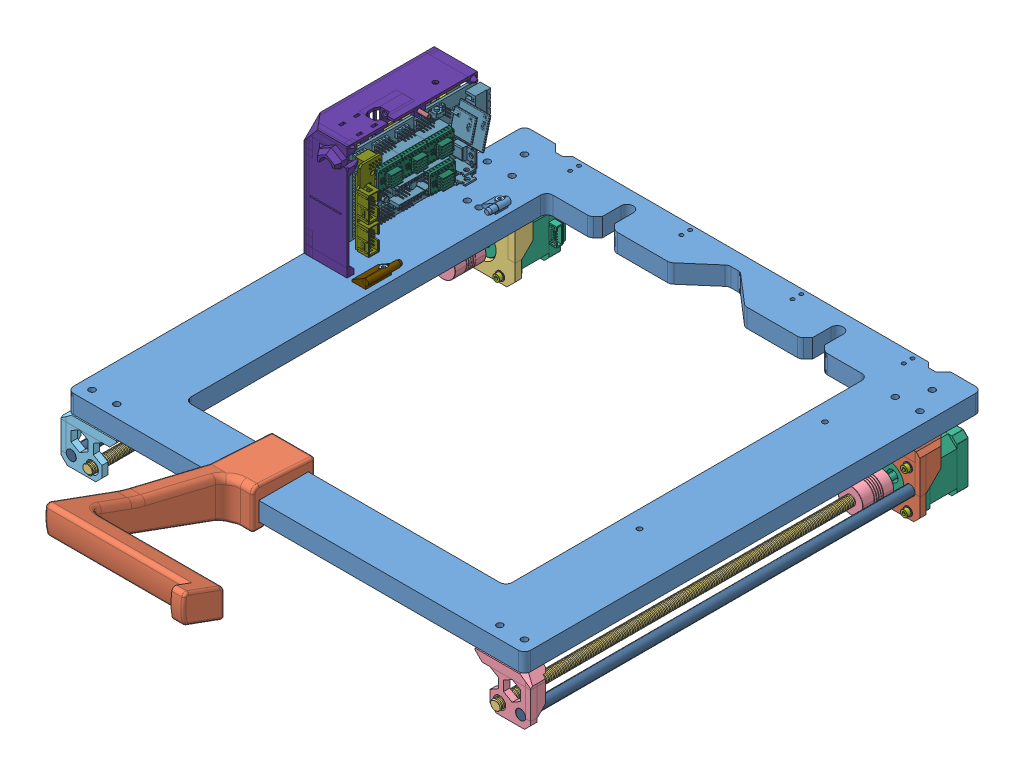
SolidWorks assembly Assembly z-axis, configuration Valor predeterminado. Lengths in mm.
Overall size (380.01 157.31 521.1).
83 component instances, 23 part files, 165 mates.
Components (placement in the parent):
- frame-2: frame [Valor predeterminado] at (-230.9594 15 -50.5362) x (1 0 0) z (0 -1 0) size (370 370 15)
- z-axis-bottom-A-1: z-axis-bottom-A [Valor predeterminado] at (185 0 55) x (0 -1 0) z (0 0 -1) size (50 52.51 38)
- z-axis-bottom-B-1: z-axis-bottom-B [Valor predeterminado] at (-198 0 55) x (0 -1 0) z (0 0 -1) size (50 52.51 38)
- z-axis-top-A-1: z-axis-top-A [Valor predeterminado] at (185 0 370) x (0 -1 0) z (0 0 -1) size (39.42 45.01 17.54)
- z-axis-top-B-1: z-axis-top-B [Valor predeterminado] at (-198 0 370) x (0 -1 0) z (0 0 -1) size (39.42 45.01 17.54)
- Stepper motor Nema 17-1: Stepper motor Nema 17 [Valor predeterminado] at (-169.2544 -5.1722 37.5) x (0 0 -1) z (1 0 0) size (62.01 42.01 48.01)
- Stepper motor Nema 17-2: Stepper motor Nema 17 [Valor predeterminado] at (169.2544 -53.4278 37.5) x (0 0 -1) z (-1 0 0) size (62.01 42.01 48.01)
- Screw DIN 912 - M3 x 10 --- 10N-1: Screw DIN 912 - M3 x 10 --- 10N [Valor predeterminado] at (-180.5 -13.8 58.5) x (0 0 1) z (-0.056546 -0.9984 0) size (13 5.5 5.5)
- Washer DIN 125A - M3-1: Washer DIN 125A - M3 [Valor predeterminado] at (-180.5 -13.8 55) x (0 0 1) z (-0.999462 0.03279 0) size (0.5 7 7)
- Screw DIN 912 - M3 x 10 --- 10N-2: Screw DIN 912 - M3 x 10 --- 10N [Valor predeterminado] at (-180.5 -44.8 58.5) x (0 0 1) z (-0.056546 -0.9984 0) size (13 5.5 5.5)
- Washer DIN 125A - M3-2: Washer DIN 125A - M3 [Valor predeterminado] at (-180.5 -44.8 55) x (0 0 1) z (-0.999462 0.03279 0) size (0.5 7 7)
- Screw DIN 912 - M3 x 10 --- 10N-3: Screw DIN 912 - M3 x 10 --- 10N [Valor predeterminado] at (-149.5 -13.8 58.5) x (0 0 1) z (-0.056546 -0.9984 0) size (13 5.5 5.5)
- Washer DIN 125A - M3-3: Washer DIN 125A - M3 [Valor predeterminado] at (-149.5 -13.8 55) x (0 0 1) z (-0.999462 0.03279 0) size (0.5 7 7)
- Screw DIN 912 - M3 x 10 --- 10N-4: Screw DIN 912 - M3 x 10 --- 10N [Valor predeterminado] at (-149.5 -44.8 58.5) x (0 0 1) z (-0.056546 -0.9984 0) size (13 5.5 5.5)
- Washer DIN 125A - M3-4: Washer DIN 125A - M3 [Valor predeterminado] at (-149.5 -44.8 55) x (0 0 1) z (-0.999462 0.03279 0) size (0.5 7 7)
- Screw DIN 912 - M3 x 10 --- 10N-5: Screw DIN 912 - M3 x 10 --- 10N [Valor predeterminado] at (149.5 -13.8 58.5) x (0 0 1) z (-0.056546 -0.9984 0) size (13 5.5 5.5)
- Washer DIN 125A - M3-5: Washer DIN 125A - M3 [Valor predeterminado] at (149.5 -13.8 55) x (0 0 1) z (-0.999462 0.03279 0) size (0.5 7 7)
- Screw DIN 912 - M3 x 10 --- 10N-6: Screw DIN 912 - M3 x 10 --- 10N [Valor predeterminado] at (180.5 -44.8 58.5) x (0 0 1) z (-0.056546 -0.9984 0) size (13 5.5 5.5)
- Washer DIN 125A - M3-6: Washer DIN 125A - M3 [Valor predeterminado] at (180.5 -44.8 55) x (0 0 1) z (-0.999462 0.03279 0) size (0.5 7 7)
- Screw DIN 912 - M3 x 10 --- 10N-7: Screw DIN 912 - M3 x 10 --- 10N [Valor predeterminado] at (149.5 -44.8 58.5) x (0 0 1) z (-0.056546 -0.9984 0) size (13 5.5 5.5)
- Washer DIN 125A - M3-7: Washer DIN 125A - M3 [Valor predeterminado] at (149.5 -44.8 55) x (0 0 1) z (-0.999462 0.03279 0) size (0.5 7 7)
- Screw DIN 912 - M3 x 10 --- 10N-8: Screw DIN 912 - M3 x 10 --- 10N [Valor predeterminado] at (180.5 -13.8 58.5) x (0 0 1) z (-0.056546 -0.9984 0) size (13 5.5 5.5)
- Washer DIN 125A - M3-8: Washer DIN 125A - M3 [Valor predeterminado] at (180.5 -13.8 55) x (0 0 1) z (-0.999462 0.03279 0) size (0.5 7 7)
- Nut DIN 934 - M3-1: Nut DIN 934 - M3 [Valor predeterminado] at (165 6.2 20) x (0 1 0) z (0.5 0 0.866025) size (2.4 5.5 6.35)
- Nut DIN 934 - M3-2: Nut DIN 934 - M3 [Valor predeterminado] at (155 6.2 40) x (0 1 0) z (0.5 0 0.866025) size (2.4 5.5 6.35)
- Nut DIN 934 - M3-3: Nut DIN 934 - M3 [Valor predeterminado] at (175 6.2 40) x (0 1 0) z (1 0 0) size (2.4 5.5 6.35)
- Nut DIN 934 - M3-4: Nut DIN 934 - M3 [Valor predeterminado] at (-165 6.2 20) x (0 1 0) z (0.5 0 -0.866025) size (2.4 5.5 6.35)
- Nut DIN 934 - M3-5: Nut DIN 934 - M3 [Valor predeterminado] at (-175 6.2 40) x (0 1 0) z (0.5 0 0.866025) size (2.4 5.5 6.35)
- Nut DIN 934 - M3-6: Nut DIN 934 - M3 [Valor predeterminado] at (-155 6.2 40) x (0 1 0) z (1 0 0) size (2.4 5.5 6.35)
- Nut DIN 934 - M3-7: Nut DIN 934 - M3 [Valor predeterminado] at (175 6.2 360) x (0 1 0) z (1 0 0) size (2.4 5.5 6.35)
- Nut DIN 934 - M3-11: Nut DIN 934 - M3 [Valor predeterminado] at (155 6.2 360) x (0 1 0) z (1 0 0) size (2.4 5.5 6.35)
- Nut DIN 934 - M3-12: Nut DIN 934 - M3 [Valor predeterminado] at (-155 6.2 360) x (0 1 0) z (0.5 0 -0.866025) size (2.4 5.5 6.35)
- Nut DIN 934 - M3-13: Nut DIN 934 - M3 [Valor predeterminado] at (-175 6.2 360) x (0 1 0) z (-0.5 0 -0.866025) size (2.4 5.5 6.35)
- Smooth Rod - 8 x 320-1: Smooth Rod - 8 x 320 [Valor predeterminado] at (-182 -29.3 210) x (0.837139 0.54699 0) z (0 0 1) size (8 8 320)
- Smooth Rod - 8 x 320-2: Smooth Rod - 8 x 320 [Valor predeterminado] at (182 -29.3 210) x (-0.0626 0.998039 0) z (0 0 1) size (8 8 320)
- Microswitch with leaver - KW11-3Z 5A 250VAC-1: Microswitch with leaver - KW11-3Z 5A 250VAC [Valor predeterminado] at (-150.8125 -3.2 77.7125) x (-1 0 0) z (0 1 0) size (21.17 22.83 6.4)
- Nut DIN 934 - M3-15: Nut DIN 934 - M3 [Valor predeterminado] at (-146.25 6.2 75.5) x (0 1 0) z (-0.866025 0 -0.5) size (2.4 5.5 6.35)
- Nut DIN 934 - M3-16: Nut DIN 934 - M3 [Valor predeterminado] at (-155.75 6.2 75.5) x (0 1 0) z (-0.866025 0 -0.5) size (2.4 5.5 6.35)
- Assembly ramps-base-1: Assembly ramps-base [Valor predeterminado] at (-197.9193 45.3991 169.7915) x (0 0 -1) z (1 0 0) size (130.96 92 50.19)
  - Arduino Mega 2560-1: Arduino Mega 2560 [Valor predeterminado] at (57.1056 8.769 22.4871) x (1 0 0) z (0 0 -1) size (107.95 53.42 12.95)
  - Screw DIN 912 - M3 x 10 --- 10N-1: Screw DIN 912 - M3 x 10 --- 10N [Valor predeterminado] at (18.65 -15.3991 25.4871) x (0 0 1) z (-0.998601 -0.052872 0) size (13 5.5 5.5)
  - Nut DIN 934 - M3-1: Nut DIN 934 - M3 [Valor predeterminado] at (18.65 -15.3991 14.6361) x (0 0 1) z (-0.5 0.866025 0) size (2.4 5.5 6.35)
  - Nut DIN 934 - M3-2: Nut DIN 934 - M3 [Valor predeterminado] at (93.7832 -15.3991 14.6361) x (0 0 1) z (0.5 0.866025 0) size (2.4 5.5 6.35)
  - Nut DIN 934 - M3-3: Nut DIN 934 - M3 [Valor predeterminado] at (93.7832 32.9371 14.6361) x (0 0 1) z (0.5 0.866025 0) size (2.4 5.5 6.35)
  - Nut DIN 934 - M3-4: Nut DIN 934 - M3 [Valor predeterminado] at (11.157 32.9371 14.6361) x (0 0 1) z (1 0 0) size (2.4 5.5 6.35)
  - Screw DIN 912 - M3 x 10 --- 10N-2: Screw DIN 912 - M3 x 10 --- 10N [Valor predeterminado] at (93.7832 -15.3991 25.4871) x (0 0 1) z (-0.973921 -0.226886 0) size (13 5.5 5.5)
  - Screw DIN 912 - M3 x 10 --- 10N-3: Screw DIN 912 - M3 x 10 --- 10N [Valor predeterminado] at (11.157 32.9371 25.4871) x (0 0 1) z (0.550712 0.834695 0) size (13 5.5 5.5)
  - Screw DIN 912 - M3 x 10 --- 10N-4: Screw DIN 912 - M3 x 10 --- 10N [Valor predeterminado] at (93.7832 32.9371 25.4871) x (0 0 1) z (0.550712 0.834695 0) size (13 5.5 5.5)
  - Screw DIN 912 - M3 x 40 --- 18N-1: Screw DIN 912 - M3 x 40 --- 18N [Valor predeterminado] at (49.8 57.6009 12.8361) x (0 0 -1) z (0.83561 0.549324 0) size (43 5.5 5.5)
  - Shield Ramps 1.4-2: Shield Ramps 1.4 [Valor predeterminado] at (108.7635 12.736 33.6033) x (0 1 0) z (1 0 0) size (61.76 37.63 106.38)
  - Driver A4988-1: Driver A4988 [Valor predeterminado] at (87.8289 82.4643 46.4093) x (-1 0 0) z (0 0 1) size (20.32 15.24 16.04)
  - Driver A4988-2: Driver A4988 [Valor predeterminado] at (108.1489 82.4643 46.4093) x (-1 0 0) z (0 0 1) size (20.32 15.24 16.04)
  - Driver A4988-3: Driver A4988 [Valor predeterminado] at (128.4689 82.4643 46.4093) x (-1 0 0) z (0 0 1) size (20.32 15.24 16.04)
  - Driver A4988-4: Driver A4988 [Valor predeterminado] at (129.5994 59.472 46.4093) x (-1 0 0) z (0 0 1) size (20.32 15.24 16.04)
  - Smart adapter conector LCD Ramps 1.4-1: Smart adapter conector LCD Ramps 1.4 [Valor predeterminado] at (11.3811 33.5685 46.6805) x (-1 0 0) z (0 1 0) size (20.12 19 60.45)
  - RAMPS-cover-base-3: RAMPS-cover-base [Valor predeterminado] at (-8.7 -30.3991 12.8361) size (126.5 92 38)
- Nut DIN 934 - M3-17: Nut DIN 934 - M3 [Valor predeterminado] at (-180.0832 20.2 161.9916) x (0 -1 0) z (0.866025 0 -0.5) size (2.4 5.5 6.35)
- Nut DIN 934 - M3-18: Nut DIN 934 - M3 [Valor predeterminado] at (-180.0832 20.2 67.9916) x (0 1 0) z (0 0 1) size (2.4 5.5 6.35)
- RAMPS-cover-hinges-A-1: RAMPS-cover-hinges-A [Valor predeterminado] at (-134.5485 20 178.9653) x (0 1 0) z (0 0 -1) size (7.4 13.4 28)
- RAMPS-cover-hinges-B-1: RAMPS-cover-hinges-B [Valor predeterminado] at (-128.5485 20 63.9653) x (0 1 0) z (0 0 1) size (7.8 13.8 17)
- Nut DIN 934 - M3-19: Nut DIN 934 - M3 [Valor predeterminado] at (-137.0485 8.8 67.9653) x (0 -1 0) z (0 0 1) size (2.4 5.5 6.35)
- Nut DIN 934 - M3-20: Nut DIN 934 - M3 [Valor predeterminado] at (-137.0485 8.8 161.9653) x (0 -1 0) z (0.866025 0 0.5) size (2.4 5.5 6.35)
- spool-holder-1: spool-holder [Valor predeterminado] at (-50 2.325 349.9) x (0 -1 0) z (-1 0 0) size (75.07 196.6 125)
- LeadScrew - 8 x 300-1: LeadScrew - 8 x 300 [Valor predeterminado] at (165 -29.3 373.6) x (0.509229 0.860631 0) z (0 0 1) size (9.24 8.22 301.1)
- LeadScrew - 8 x 300-2: LeadScrew - 8 x 300 [Valor predeterminado] at (-165 -29.3 373.6) x (-0.382268 -0.924051 0) z (0 0 1) size (9.24 8.22 301.1)
- Flexible coupler - 5 x 8-1: Flexible coupler - 5 x 8 [Valor predeterminado] at (-163.6049 -28.4539 61.1) x (0.99991 -0.013416 0) z (0 0 1) size (20 20.77 25)
- Flexible coupler - 5 x 8-2: Flexible coupler - 5 x 8 [Valor predeterminado] at (166.3519 -28.3864 61.1) x (0.999363 0.035693 0) z (0 0 1) size (20 20.77 25)
- Screw DIN 912 - M3 x 16 --- 16N-1: Screw DIN 912 - M3 x 16 --- 16N [Valor predeterminado] at (-155 -7 360) x (0 -1 0) z (-0.591205 0 0.806522) size (19 5.5 5.5)
- Screw DIN 912 - M3 x 16 --- 16N-2: Screw DIN 912 - M3 x 16 --- 16N [Valor predeterminado] at (-175 -7 360) x (0 -1 0) z (-0.591205 0 0.806522) size (19 5.5 5.5)
- Screw DIN 912 - M3 x 16 --- 16N-3: Screw DIN 912 - M3 x 16 --- 16N [Valor predeterminado] at (155 -7 360) x (0 -1 0) z (-0.591205 0 0.806522) size (19 5.5 5.5)
- Screw DIN 912 - M3 x 16 --- 16N-4: Screw DIN 912 - M3 x 16 --- 16N [Valor predeterminado] at (175 -7 360) x (0 -1 0) z (-0.591205 0 0.806522) size (19 5.5 5.5)
- Screw DIN 912 - M3 x 16 --- 16N-5: Screw DIN 912 - M3 x 16 --- 16N [Valor predeterminado] at (175 -7 40) x (0 -1 0) z (-0.591205 0 0.806522) size (19 5.5 5.5)
- Screw DIN 912 - M3 x 16 --- 16N-6: Screw DIN 912 - M3 x 16 --- 16N [Valor predeterminado] at (165 -7 20) x (0 -1 0) z (-0.591205 0 0.806522) size (19 5.5 5.5)
- Screw DIN 912 - M3 x 16 --- 16N-7: Screw DIN 912 - M3 x 16 --- 16N [Valor predeterminado] at (155 -7 40) x (0 -1 0) z (-0.591205 0 0.806522) size (19 5.5 5.5)
- Screw DIN 912 - M3 x 16 --- 16N-8: Screw DIN 912 - M3 x 16 --- 16N [Valor predeterminado] at (-155 -7 40) x (0 -1 0) z (-0.591205 0 0.806522) size (19 5.5 5.5)
- Screw DIN 912 - M3 x 16 --- 16N-9: Screw DIN 912 - M3 x 16 --- 16N [Valor predeterminado] at (-165 -7 20) x (0 -1 0) z (0.85743 0 -0.5146) size (19 5.5 5.5)
- Screw DIN 912 - M3 x 16 --- 16N-10: Screw DIN 912 - M3 x 16 --- 16N [Valor predeterminado] at (-175 -7 40) x (0 -1 0) z (-0.591205 0 0.806522) size (19 5.5 5.5)
- Screw DIN 912 - M3 x 16 --- 16N-11: Screw DIN 912 - M3 x 16 --- 16N [Valor predeterminado] at (-137.0485 22 67.9653) x (0 1 0) z (-0.552016 0 0.833834) size (19 5.5 5.5)
- Screw DIN 912 - M3 x 16 --- 16N-12: Screw DIN 912 - M3 x 16 --- 16N [Valor predeterminado] at (-137.0485 21 161.9653) x (0 1 0) z (0.888501 0 0.458875) size (19 5.5 5.5)
- Screw DIN 912 - M3 x 16 --- 16N-13: Screw DIN 912 - M3 x 16 --- 16N [Valor predeterminado] at (-146.225 -9.4 75.5) x (0 -1 0) z (0.477506 0 0.878629) size (19 5.5 5.5)
- Screw DIN 912 - M3 x 16 --- 16N-14: Screw DIN 912 - M3 x 16 --- 16N [Valor predeterminado] at (-155.75 -9.4 75.5) x (0 -1 0) z (-0.13071 0 0.991421) size (19 5.5 5.5)
- Screw DIN 912 - M3 x 16 --- 16N-15: Screw DIN 912 - M3 x 16 --- 16N [Valor predeterminado] at (-180.0832 7 67.9916) x (0 -1 0) z (-0.148109 0 0.988971) size (19 5.5 5.5)
- Screw DIN 912 - M3 x 16 --- 16N-16: Screw DIN 912 - M3 x 16 --- 16N [Valor predeterminado] at (-180.0485 7 161.9653) x (0 -1 0) z (0.028079 0 0.999606) size (19 5.5 5.5)
Mates (geometry in assembly coordinates):
- Coincidente1: coincident: plane of assembly through (0 0 0) normal (0 0 1); plane of frame-2 through (-160 0 0) normal (0 0 -1); plane of assembly
- Simétrico1: symmetric: plane of assembly; plane of assembly; plane of frame-2 through (185 0 365) normal (1 0 0); plane of frame-2 through (-185 0 5) normal (-1 0 0); plane of assembly
- Coincidente2: coincident: plane of assembly through (0 0 0) normal (0 1 0); plane of frame-2 through (180 0 365) normal (0 -1 0); plane of assembly
- Coincidente3: coincident: plane of assembly; plane of assembly; plane of frame-2 through (180 0 365) normal (0 -1 0); plane of z-axis-bottom-B-1 through (-186.5 0 55) normal (0 1 0)
- Coincidente4: coincident: plane of assembly; plane of assembly; plane of frame-2 through (180 0 365) normal (0 -1 0); plane of z-axis-bottom-A-1 through (186.5 0 55) normal (0 1 0)
- Coincidente5: coincident: plane of assembly through (0 0 0) normal (0 1 0); plane of z-axis-top-A-1 through (190 0 370) normal (0 1 0); plane of assembly
- Coincidente6: coincident: plane of assembly through (0 0 0) normal (0 1 0); plane of z-axis-top-B-1 through (-190 0 370) normal (0 1 0); plane of assembly
- Paralelo1: parallel: plane of assembly through (0 0 0) normal (0 0 1); plane of z-axis-bottom-A-1 through (186.5 0 55) normal (0 0 1); plane of assembly
- Paralelo2: parallel: plane of assembly through (0 0 0) normal (0 0 1); plane of z-axis-bottom-B-1 through (-186.5 0 55) normal (0 0 1); plane of assembly
- Concêntrico1: concentric: cylinder of assembly; cylinder of assembly; cylinder of frame-2 through (-165 0 20) axis (0 1 0) radius 1.5; cylinder of z-axis-bottom-B-1 through (-165 1 20) axis (0 -1 0) radius 1.8
- Concêntrico2: concentric: cylinder of assembly; cylinder of assembly; cylinder of frame-2 through (165 0 20) axis (0 1 0) radius 1.5; cylinder of z-axis-bottom-A-1 through (165 1 20) axis (0 -1 0) radius 1.8
- Paralelo3: parallel: plane of assembly through (0 0 0) normal (0 0 1); plane of z-axis-top-B-1 through (-190 0 370) normal (0 0 1); plane of assembly
- Paralelo4: parallel: plane of assembly through (0 0 0) normal (0 0 1); plane of z-axis-top-A-1 through (190 0 370) normal (0 0 1); plane of assembly
- Concêntrico3: concentric: cylinder of assembly; cylinder of assembly; cylinder of frame-2 through (-155 0 360) axis (0 1 0) radius 1.5; cylinder of z-axis-top-B-1 through (-155 1 360) axis (0 -1 0) radius 1.8
- Concêntrico4: concentric: cylinder of assembly; cylinder of assembly; cylinder of frame-2 through (155 0 360) axis (0 1 0) radius 1.5; cylinder of z-axis-top-A-1 through (155 1 360) axis (0 -1 0) radius 1.8
- Coincidente11: coincident: plane of assembly; plane of assembly; plane of z-axis-bottom-B-1 through (-190 0 50) normal (0 0 -1); plane of Stepper motor Nema 17-1 through (-165 -29.3 50) normal (0 0 1)
- Concêntrico5: concentric: cylinder of assembly; cylinder of assembly; cylinder of z-axis-bottom-B-1 through (-165 -29.3 57) axis (0 0 -1) radius 12; cylinder of Stepper motor Nema 17-1 through (-165 -29.3 50.85) axis (0 0 1) radius 11
- Concêntrico6: concentric: cylinder of assembly; cylinder of assembly; cylinder of z-axis-bottom-A-1 through (165 -29.3 57) axis (0 0 -1) radius 12; cylinder of Stepper motor Nema 17-2 through (165 -29.3 50.85) axis (0 0 1) radius 11
- Coincidente13: coincident: plane of assembly; plane of assembly; plane of z-axis-bottom-A-1 through (190 0 50) normal (0 0 -1); plane of Stepper motor Nema 17-2 through (165 -29.3 50) normal (0 0 1)
- Concêntrico7: concentric: cylinder of assembly; cylinder of assembly; cylinder of Screw DIN 912 - M3 x 10 --- 10N-1 through (-180.5 -13.8 58.5) axis (0 0 1) radius 1.5; cylinder of Washer DIN 125A - M3-1 through (-180.5 -13.8 55.5) axis (0 0 -1) radius 1.6
- Coincidente14: coincident: plane of assembly; plane of assembly; plane of Screw DIN 912 - M3 x 10 --- 10N-1 through (-183.2456 -13.6445 55.5) normal (0 0 -1); plane of Washer DIN 125A - M3-1 through (-180.5 -13.8 55.5) normal (0 0 1)
- Concêntrico8: concentric: cylinder of assembly; cylinder of assembly; cylinder of z-axis-bottom-B-1 through (-180.5 -13.8 57) axis (0 0 -1) radius 1.8; cylinder of Screw DIN 912 - M3 x 10 --- 10N-1 through (-180.5 -13.8 58.5) axis (0 0 1) radius 1.5
- Coincidente15: coincident: plane of assembly; plane of assembly; plane of z-axis-bottom-B-1 through (-190 0 55) normal (0 0 1); plane of Washer DIN 125A - M3-1 through (-180.5 -13.8 55) normal (0 0 -1)
- Concêntrico9: concentric: cylinder of assembly; cylinder of assembly; cylinder of Screw DIN 912 - M3 x 10 --- 10N-2 through (-180.5 -44.8 58.5) axis (0 0 1) radius 1.5; cylinder of Washer DIN 125A - M3-2 through (-180.5 -44.8 55.5) axis (0 0 -1) radius 1.6
- Coincidente16: coincident: plane of assembly; plane of assembly; plane of Screw DIN 912 - M3 x 10 --- 10N-2 through (-183.2456 -44.6445 55.5) normal (0 0 -1); plane of Washer DIN 125A - M3-2 through (-180.5 -44.8 55.5) normal (0 0 1)
- Concêntrico10: concentric: cylinder of assembly; cylinder of assembly; cylinder of Screw DIN 912 - M3 x 10 --- 10N-3 through (-149.5 -13.8 58.5) axis (0 0 1) radius 1.5; cylinder of Washer DIN 125A - M3-3 through (-149.5 -13.8 55.5) axis (0 0 -1) radius 1.6
- Coincidente17: coincident: plane of assembly; plane of assembly; plane of Screw DIN 912 - M3 x 10 --- 10N-3 through (-152.2456 -13.6445 55.5) normal (0 0 -1); plane of Washer DIN 125A - M3-3 through (-149.5 -13.8 55.5) normal (0 0 1)
- Concêntrico11: concentric: cylinder of assembly; cylinder of assembly; cylinder of Screw DIN 912 - M3 x 10 --- 10N-4 through (-149.5 -44.8 58.5) axis (0 0 1) radius 1.5; cylinder of Washer DIN 125A - M3-4 through (-149.5 -44.8 55.5) axis (0 0 -1) radius 1.6
- Coincidente18: coincident: plane of assembly; plane of assembly; plane of Screw DIN 912 - M3 x 10 --- 10N-4 through (-152.2456 -44.6445 55.5) normal (0 0 -1); plane of Washer DIN 125A - M3-4 through (-149.5 -44.8 55.5) normal (0 0 1)
- Concêntrico12: concentric: cylinder of assembly; cylinder of assembly; cylinder of z-axis-bottom-B-1 through (-180.5 -44.8 57) axis (0 0 -1) radius 1.8; cylinder of Screw DIN 912 - M3 x 10 --- 10N-2 through (-180.5 -44.8 58.5) axis (0 0 1) radius 1.5
- Concêntrico13: concentric: cylinder of assembly; cylinder of assembly; cylinder of z-axis-bottom-B-1 through (-149.5 -44.8 57) axis (0 0 -1) radius 1.8; cylinder of Screw DIN 912 - M3 x 10 --- 10N-4 through (-149.5 -44.8 58.5) axis (0 0 1) radius 1.5
- Concêntrico14: concentric: cylinder of assembly; cylinder of assembly; cylinder of z-axis-bottom-B-1 through (-149.5 -13.8 57) axis (0 0 -1) radius 1.8; cylinder of Screw DIN 912 - M3 x 10 --- 10N-3 through (-149.5 -13.8 58.5) axis (0 0 1) radius 1.5
- Coincidente19: coincident: plane of assembly; plane of assembly; plane of z-axis-bottom-B-1 through (-190 0 55) normal (0 0 1); plane of Washer DIN 125A - M3-4 through (-149.5 -44.8 55) normal (0 0 -1)
- Coincidente20: coincident: plane of assembly; plane of assembly; plane of z-axis-bottom-B-1 through (-190 0 55) normal (0 0 1); plane of Washer DIN 125A - M3-2 through (-180.5 -44.8 55) normal (0 0 -1)
- Coincidente21: coincident: plane of assembly; plane of assembly; plane of z-axis-bottom-B-1 through (-190 0 55) normal (0 0 1); plane of Washer DIN 125A - M3-3 through (-149.5 -13.8 55) normal (0 0 -1)
- Concêntrico15: concentric: cylinder of assembly; cylinder of assembly; cylinder of Screw DIN 912 - M3 x 10 --- 10N-5 through (149.5 -13.8 58.5) axis (0 0 1) radius 1.5; cylinder of Washer DIN 125A - M3-5 through (149.5 -13.8 55.5) axis (0 0 -1) radius 1.6
- Coincidente22: coincident: plane of assembly; plane of assembly; plane of Screw DIN 912 - M3 x 10 --- 10N-5 through (146.7544 -13.6445 55.5) normal (0 0 -1); plane of Washer DIN 125A - M3-5 through (149.5 -13.8 55.5) normal (0 0 1)
- Concêntrico16: concentric: cylinder of assembly; cylinder of assembly; cylinder of Screw DIN 912 - M3 x 10 --- 10N-6 through (180.5 -44.8 58.5) axis (0 0 1) radius 1.5; cylinder of Washer DIN 125A - M3-6 through (180.5 -44.8 55.5) axis (0 0 -1) radius 1.6
- Coincidente23: coincident: plane of assembly; plane of assembly; plane of Screw DIN 912 - M3 x 10 --- 10N-6 through (177.7544 -44.6445 55.5) normal (0 0 -1); plane of Washer DIN 125A - M3-6 through (180.5 -44.8 55.5) normal (0 0 1)
- Concêntrico17: concentric: cylinder of assembly; cylinder of assembly; cylinder of Screw DIN 912 - M3 x 10 --- 10N-7 through (149.5 -44.8 58.5) axis (0 0 1) radius 1.5; cylinder of Washer DIN 125A - M3-7 through (149.5 -44.8 55.5) axis (0 0 -1) radius 1.6
- Coincidente24: coincident: plane of assembly; plane of assembly; plane of Screw DIN 912 - M3 x 10 --- 10N-7 through (146.7544 -44.6445 55.5) normal (0 0 -1); plane of Washer DIN 125A - M3-7 through (149.5 -44.8 55.5) normal (0 0 1)
- Concêntrico18: concentric: cylinder of assembly; cylinder of assembly; cylinder of Screw DIN 912 - M3 x 10 --- 10N-8 through (180.5 -13.8 58.5) axis (0 0 1) radius 1.5; cylinder of Washer DIN 125A - M3-8 through (180.5 -13.8 55.5) axis (0 0 -1) radius 1.6
- Coincidente25: coincident: plane of assembly; plane of assembly; plane of Screw DIN 912 - M3 x 10 --- 10N-8 through (177.7544 -13.6445 55.5) normal (0 0 -1); plane of Washer DIN 125A - M3-8 through (180.5 -13.8 55.5) normal (0 0 1)
- Concêntrico19: concentric: cylinder of assembly; cylinder of assembly; cylinder of z-axis-bottom-A-1 through (149.5 -13.8 57) axis (0 0 -1) radius 1.8; cylinder of Screw DIN 912 - M3 x 10 --- 10N-5 through (149.5 -13.8 58.5) axis (0 0 1) radius 1.5
- Concêntrico20: concentric: cylinder of assembly; cylinder of assembly; cylinder of z-axis-bottom-A-1 through (180.5 -13.8 57) axis (0 0 -1) radius 1.8; cylinder of Screw DIN 912 - M3 x 10 --- 10N-8 through (180.5 -13.8 58.5) axis (0 0 1) radius 1.5
- Concêntrico21: concentric: cylinder of assembly; cylinder of assembly; cylinder of z-axis-bottom-A-1 through (180.5 -44.8 57) axis (0 0 -1) radius 1.8; cylinder of Screw DIN 912 - M3 x 10 --- 10N-6 through (180.5 -44.8 58.5) axis (0 0 1) radius 1.5
- Concêntrico22: concentric: cylinder of assembly; cylinder of assembly; cylinder of z-axis-bottom-A-1 through (149.5 -44.8 57) axis (0 0 -1) radius 1.8; cylinder of Screw DIN 912 - M3 x 10 --- 10N-7 through (149.5 -44.8 58.5) axis (0 0 1) radius 1.5
- Coincidente26: coincident: plane of assembly; plane of assembly; plane of z-axis-bottom-A-1 through (190 0 55) normal (0 0 1); plane of Washer DIN 125A - M3-6 through (180.5 -44.8 55) normal (0 0 -1)
- Coincidente27: coincident: plane of assembly; plane of assembly; plane of z-axis-bottom-A-1 through (190 0 55) normal (0 0 1); plane of Washer DIN 125A - M3-7 through (149.5 -44.8 55) normal (0 0 -1)
- Coincidente28: coincident: plane of assembly; plane of assembly; plane of z-axis-bottom-A-1 through (190 0 55) normal (0 0 1); plane of Washer DIN 125A - M3-5 through (149.5 -13.8 55) normal (0 0 -1)
- Coincidente29: coincident: plane of assembly; plane of assembly; plane of z-axis-bottom-A-1 through (190 0 55) normal (0 0 1); plane of Washer DIN 125A - M3-8 through (180.5 -13.8 55) normal (0 0 -1)
- Concêntrico62: concentric: cylinder of assembly; cylinder of assembly; cylinder of z-axis-bottom-B-1 through (-182 -29.3 56) axis (0 0 -1) radius 4.125; cylinder of Smooth Rod - 8 x 320-1 through (-182 -29.3 370) axis (0 0 -1) radius 4
- Coincidente74: coincident: plane of assembly; plane of assembly; plane of Stepper motor Nema 17-1 through (-165 -29.3 50) normal (0 0 1); plane of Smooth Rod - 8 x 320-1 through (-182 -29.3 50) normal (0 0 -1)
- Concêntrico63: concentric: cylinder of assembly; cylinder of assembly; cylinder of z-axis-bottom-A-1 through (182 -29.3 56) axis (0 0 -1) radius 4.125; cylinder of Smooth Rod - 8 x 320-2 through (182 -29.3 370) axis (0 0 -1) radius 4
- Coincidente75: coincident: plane of assembly; plane of assembly; plane of Stepper motor Nema 17-2 through (165 -29.3 50) normal (0 0 1); plane of Smooth Rod - 8 x 320-2 through (182 -29.3 50) normal (0 0 -1)
- Coincidente86: coincident: plane of assembly; plane of assembly; plane of frame-2 through (180 0 365) normal (0 -1 0); plane of Microswitch with leaver - KW11-3Z 5A 250VAC-1 through (-146.225 0 74.3604) normal (0 1 0)
- Paralelo7: parallel: plane of assembly through (0 0 0) normal (0 0 1); plane of Microswitch with leaver - KW11-3Z 5A 250VAC-1 through (-160.9125 -3.2 82.0625) normal (0 0 1); plane of assembly
- Concêntrico75: concentric: cylinder of assembly; cylinder of assembly; cylinder of frame-2 through (-155.75 0 75.5) axis (0 1 0) radius 1.5; cylinder of Microswitch with leaver - KW11-3Z 5A 250VAC-1 through (-155.75 0 75.5) axis (0 -1 0) radius 1.175
- Coincidente97: coincident: plane of frame-2 through (180 15 365) normal (0 1 0); plane of Assembly ramps-base-1/RAMPS-cover-base-3 through (-185.0832 15 177.4916) normal (0 -1 0)
- Paralelo9: parallel: plane of frame-2 through (-185 0 5) normal (-1 0 0); plane of Assembly ramps-base-1/RAMPS-cover-base-3 through (-185.0832 15 178.4916) normal (-1 0 0)
- Concêntrico84: concentric: cylinder of frame-2 through (-180.0832 0 67.9916) axis (0 1 0) radius 1.5; cylinder of Assembly ramps-base-1/RAMPS-cover-base-3 through (-180.0832 24 67.9916) axis (0 -1 0) radius 1.6
- Coincidente104: coincident: plane of Assembly ramps-base-1/RAMPS-cover-base-3 through (-185.0832 19 177.4916) normal (0 1 0); unknown of ?
- Coincidente105: coincident: plane of Assembly ramps-base-1/RAMPS-cover-base-3 through (-185.0832 19 80.4916) normal (0 1 0); plane of ? through (-178.8866 19 70.9329) normal (0 -1 0)
- Coincidente106: coincident: plane of assembly; plane of assembly; plane of frame-2 through (180 15 365) normal (0 1 0); plane of RAMPS-cover-hinges-A-1 through (-145.5485 15 178.9653) normal (0 -1 0)
- Paralelo10: parallel: plane of assembly; plane of assembly; plane of frame-2 through (-130 0 42) normal (1 0 0); plane of RAMPS-cover-hinges-A-1 through (-134.5485 15 178.9653) normal (1 0 0)
- Concêntrico92: concentric: cylinder of assembly; cylinder of assembly; cylinder of frame-2 through (-137.0485 0 161.9653) axis (0 1 0) radius 1.5; cylinder of RAMPS-cover-hinges-A-1 through (-137.0485 7.5 161.9653) axis (0 1 0) radius 1.7
- Concêntrico93: concentric: cylinder of assembly; cylinder of assembly; cylinder of frame-2 through (-137.0485 0 67.9653) axis (0 1 0) radius 1.5; cylinder of RAMPS-cover-hinges-B-1 through (-137.0485 8 67.9653) axis (0 1 0) radius 1.5
- Paralelo11: parallel: plane of assembly; plane of assembly; plane of frame-2 through (-130 0 42) normal (1 0 0); plane of RAMPS-cover-hinges-B-1 through (-134.5485 15 63.9653) normal (1 0 0)
- Coincidente109: coincident: plane of assembly; plane of assembly; plane of frame-2 through (180 15 365) normal (0 1 0); plane of RAMPS-cover-hinges-B-1 through (-134.5485 15 63.9653) normal (0 -1 0)
- Coincidente123: coincident: plane of assembly; plane of assembly; plane of frame-2 through (-180 0 370) normal (0 0 1); plane of spool-holder-1 through (-30 -1 370) normal (0 0 -1)
- Coincidente124: coincident: plane of assembly; plane of assembly; plane of frame-2 through (180 15 365) normal (0 1 0); plane of spool-holder-1 through (-30 15 370) normal (0 -1 0)
- Coincidente125: coincident: plane of assembly through (0 0 0) normal (1 0 0); plane of spool-holder-1 through (0 2.325 349.9) normal (1 0 0); plane of assembly
- Coincidente126: coincident: plane of assembly; plane of assembly; plane of frame-2 through (180 15 365) normal (0 1 0); plane of Assembly ramps-base-1/RAMPS-cover-base-3 through (-185.0832 15 177.4916) normal (0 -1 0)
- Paralelo13: parallel: plane of assembly; plane of assembly; plane of frame-2 through (-185 0 5) normal (-1 0 0); plane of Assembly ramps-base-1/RAMPS-cover-base-3 through (-185.0832 15 178.4916) normal (-1 0 0)
- Coincidente129: coincident: plane of assembly; plane of assembly; plane of Assembly ramps-base-1/RAMPS-cover-base-3 through (-185.0832 19 80.4916) normal (0 1 0); plane of Nut DIN 934 - M3-18 through (-177.3332 19 66.4038) normal (0 -1 0)
- Coincidente130: coincident: plane of assembly; plane of assembly; plane of Assembly ramps-base-1/RAMPS-cover-base-3 through (-185.0832 19 177.4916) normal (0 1 0); plane of Nut DIN 934 - M3-17 through (-180.0832 19 165.167) normal (0 -1 0)
- Concêntrico108: concentric: cylinder of assembly; cylinder of assembly; cylinder of Stepper motor Nema 17-2 through (165 -29.3 45.6) axis (0 0 -1) radius 2.5; cylinder of LeadScrew - 8 x 300-1 through (165 -29.3 73.6) axis (0 0 1) radius 4
- Coincidente131: coincident: plane of assembly; plane of assembly; plane of Stepper motor Nema 17-2 through (169.2544 -53.4278 73.6) normal (0 0 1); plane of LeadScrew - 8 x 300-1 through (165 -29.3 73.6) normal (0 0 -1)
- Concêntrico109: concentric: cylinder of assembly; cylinder of assembly; cylinder of Stepper motor Nema 17-1 through (-165 -29.3 45.6) axis (0 0 -1) radius 2.5; cylinder of LeadScrew - 8 x 300-2 through (-165 -29.3 73.6) axis (0 0 1) radius 4
- Coincidente132: coincident: plane of assembly; plane of assembly; plane of Stepper motor Nema 17-1 through (-169.2544 -5.1722 73.6) normal (0 0 1); plane of LeadScrew - 8 x 300-2 through (-165 -29.3 73.6) normal (0 0 -1)
- Concêntrico110: concentric: cylinder of assembly; cylinder of assembly; cylinder of Stepper motor Nema 17-1 through (-165 -29.3 45.6) axis (0 0 -1) radius 2.5; cylinder of Flexible coupler - 5 x 8-1 through (-165 -29.3 86.1) axis (0 0 -1) radius 2.5
- Concêntrico111: concentric: cylinder of assembly; cylinder of assembly; cylinder of Stepper motor Nema 17-2 through (165 -29.3 45.6) axis (0 0 -1) radius 2.5; cylinder of Flexible coupler - 5 x 8-2 through (165 -29.3 86.1) axis (0 0 -1) radius 2.5
- Coincidente133: coincident: plane of assembly; plane of assembly; plane of Stepper motor Nema 17-2 through (169.2544 -53.4278 73.6) normal (0 0 1); plane of Flexible coupler - 5 x 8-2 through (166.3519 -28.3864 73.6) normal (0 0 1)
- Coincidente134: coincident: plane of assembly; plane of assembly; plane of Stepper motor Nema 17-1 through (-169.2544 -5.1722 73.6) normal (0 0 1); plane of Flexible coupler - 5 x 8-1 through (-163.6049 -28.4539 73.6) normal (0 0 1)
- Paralelo14: parallel: plane of assembly; plane of assembly; plane of frame-2 through (180 0 365) normal (0 -1 0); plane of Stepper motor Nema 17-2 through (186 -50.3 21.1) normal (0 -1 0)
- Paralelo15: parallel: plane of assembly; plane of assembly; plane of frame-2 through (180 0 365) normal (0 -1 0); plane of Stepper motor Nema 17-1 through (-144 -50.3 21.1) normal (0 -1 0)
- Coincidente138: coincident: plane of assembly; plane of assembly; plane of frame-2 through (165 5 20) normal (0 1 0); plane of Nut DIN 934 - M3-1 through (166.5877 5 17.25) normal (0 -1 0)
- Coincidente139: coincident: plane of assembly; plane of assembly; plane of frame-2 through (155 5 40) normal (0 1 0); plane of Nut DIN 934 - M3-2 through (156.5877 5 37.25) normal (0 -1 0)
- Coincidente140: coincident: plane of assembly; plane of assembly; plane of frame-2 through (175 5 40) normal (0 1 0); plane of Nut DIN 934 - M3-3 through (173.4123 5 37.25) normal (0 -1 0)
- Paralelo19: parallel: plane of frame-2 through (144 0 2) normal (0 0 -1); plane of Nut DIN 934 - M3-1 through (166.5877 7.4 17.25) normal (0 0 -1)
- Paralelo20: parallel: plane of frame-2 through (144 0 2) normal (0 0 -1); plane of Nut DIN 934 - M3-2 through (156.5877 7.4 37.25) normal (0 0 -1)
- Paralelo21: parallel: plane of frame-2 through (144 0 2) normal (0 0 -1); plane of Nut DIN 934 - M3-3 through (176.5877 7.4 37.25) normal (0 0 -1)
- Paralelo22: parallel: plane of assembly; plane of assembly; plane of frame-2 through (144 0 2) normal (0 0 -1); plane of Nut DIN 934 - M3-4 through (-163.4123 7.4 17.25) normal (0 0 -1)
- Paralelo23: parallel: plane of assembly; plane of assembly; plane of frame-2 through (144 0 2) normal (0 0 -1); plane of Nut DIN 934 - M3-6 through (-153.4123 7.4 37.25) normal (0 0 -1)
- Paralelo24: parallel: plane of assembly; plane of assembly; plane of frame-2 through (144 0 2) normal (0 0 -1); plane of Nut DIN 934 - M3-5 through (-173.4123 7.4 37.25) normal (0 0 -1)
- Coincidente148: coincident: plane of frame-2 through (-165 5 20) normal (0 1 0); plane of Nut DIN 934 - M3-4 through (-168.1754 5 20) normal (0 -1 0)
- Coincidente149: coincident: plane of frame-2 through (-175 5 40) normal (0 1 0); plane of Nut DIN 934 - M3-5 through (-173.4123 5 37.25) normal (0 -1 0)
- Coincidente151: coincident: plane of frame-2 through (-155 5 40) normal (0 1 0); plane of Nut DIN 934 - M3-6 through (-156.5877 5 37.25) normal (0 -1 0)
- Concêntrico112: concentric: cylinder of frame-2 through (-165 5 20) axis (0 1 0) radius 2.5; cylinder of Nut DIN 934 - M3-4 through (-165 7.4 20) axis (0 -1 0) radius 1.25
- Concêntrico113: concentric: cylinder of frame-2 through (-175 5 40) axis (0 1 0) radius 2.5; cylinder of Nut DIN 934 - M3-5 through (-175 7.4 40) axis (0 -1 0) radius 1.25
- Concêntrico114: concentric: cylinder of frame-2 through (-155 5 40) axis (0 1 0) radius 2.5; cylinder of Nut DIN 934 - M3-6 through (-155 7.4 40) axis (0 -1 0) radius 1.25
- Concêntrico115: concentric: cylinder of frame-2 through (175 5 40) axis (0 1 0) radius 2.5; cylinder of Nut DIN 934 - M3-3 through (175 7.4 40) axis (0 -1 0) radius 1.25
- Concêntrico116: concentric: cylinder of frame-2 through (155 5 40) axis (0 1 0) radius 2.5; cylinder of Nut DIN 934 - M3-2 through (155 7.4 40) axis (0 -1 0) radius 1.25
- Concêntrico117: concentric: cylinder of frame-2 through (165 5 20) axis (0 1 0) radius 2.5; cylinder of Nut DIN 934 - M3-1 through (165 7.4 20) axis (0 -1 0) radius 1.25
- Concêntrico118: concentric: cylinder of assembly; cylinder of assembly; cylinder of frame-2 through (-175 5 360) axis (0 1 0) radius 2.5; cylinder of Nut DIN 934 - M3-13 through (-175 7.4 360) axis (0 -1 0) radius 1.25
- Concêntrico119: concentric: cylinder of assembly; cylinder of assembly; cylinder of frame-2 through (-155 5 360) axis (0 1 0) radius 2.5; cylinder of Nut DIN 934 - M3-12 through (-155 7.4 360) axis (0 -1 0) radius 1.25
- Paralelo25: parallel: plane of frame-2 through (-180 0 370) normal (0 0 1); plane of Nut DIN 934 - M3-12 through (-156.5877 7.4 362.75) normal (0 0 1)
- Paralelo26: parallel: plane of frame-2 through (-180 0 370) normal (0 0 1); plane of Nut DIN 934 - M3-13 through (-176.5877 7.4 362.75) normal (0 0 1)
- Coincidente154: coincident: plane of frame-2 through (-155 5 360) normal (0 1 0); plane of Nut DIN 934 - M3-12 through (-158.1754 5 360) normal (0 -1 0)
- Coincidente155: coincident: plane of frame-2 through (-175 5 360) normal (0 1 0); plane of Nut DIN 934 - M3-13 through (-176.5877 5 362.75) normal (0 -1 0)
- Concêntrico120: concentric: cylinder of assembly; cylinder of assembly; cylinder of frame-2 through (155 5 360) axis (0 1 0) radius 2.5; cylinder of Nut DIN 934 - M3-11 through (155 7.4 360) axis (0 -1 0) radius 1.25
- Concêntrico121: concentric: cylinder of assembly; cylinder of assembly; cylinder of frame-2 through (175 5 360) axis (0 1 0) radius 2.5; cylinder of Nut DIN 934 - M3-7 through (175 7.4 360) axis (0 -1 0) radius 1.25
- Paralelo27: parallel: plane of frame-2 through (-180 0 370) normal (0 0 1); plane of Nut DIN 934 - M3-7 through (173.4123 7.4 362.75) normal (0 0 1)
- Paralelo28: parallel: plane of frame-2 through (-180 0 370) normal (0 0 1); plane of Nut DIN 934 - M3-11 through (153.4123 7.4 362.75) normal (0 0 1)
- Coincidente158: coincident: plane of frame-2 through (175 5 360) normal (0 1 0); plane of Nut DIN 934 - M3-7 through (173.4123 5 357.25) normal (0 -1 0)
- Coincidente159: coincident: plane of frame-2 through (155 5 360) normal (0 1 0); plane of Nut DIN 934 - M3-11 through (153.4123 5 357.25) normal (0 -1 0)
- Concêntrico122: concentric: cylinder of assembly; cylinder of assembly; cylinder of z-axis-top-B-1 through (-155 1 360) axis (0 -1 0) radius 1.8; cylinder of Screw DIN 912 - M3 x 16 --- 16N-1 through (-155 -7 360) axis (0 -1 0) radius 1.5
- Coincidente160: coincident: plane of z-axis-top-B-1 through (-155 -4 360) normal (0 -1 0); plane of Screw DIN 912 - M3 x 16 --- 16N-1 through (-152.7821 -4 361.6258) normal (0 1 0)
- Concêntrico123: concentric: cylinder of assembly; cylinder of assembly; cylinder of z-axis-top-B-1 through (-175 1 360) axis (0 -1 0) radius 1.8; cylinder of Screw DIN 912 - M3 x 16 --- 16N-2 through (-175 -7 360) axis (0 -1 0) radius 1.5
- Concêntrico124: concentric: cylinder of assembly; cylinder of assembly; cylinder of z-axis-top-A-1 through (175 1 360) axis (0 -1 0) radius 1.8; cylinder of Screw DIN 912 - M3 x 16 --- 16N-4 through (175 -7 360) axis (0 -1 0) radius 1.5
- Concêntrico125: concentric: cylinder of assembly; cylinder of assembly; cylinder of z-axis-top-A-1 through (155 1 360) axis (0 -1 0) radius 1.8; cylinder of Screw DIN 912 - M3 x 16 --- 16N-3 through (155 -7 360) axis (0 -1 0) radius 1.5
- Concêntrico126: concentric: cylinder of assembly; cylinder of assembly; cylinder of z-axis-bottom-A-1 through (175 1 40) axis (0 -1 0) radius 1.8; cylinder of Screw DIN 912 - M3 x 16 --- 16N-5 through (175 -7 40) axis (0 -1 0) radius 1.5
- Concêntrico127: concentric: cylinder of assembly; cylinder of assembly; cylinder of z-axis-bottom-A-1 through (155 1 40) axis (0 -1 0) radius 1.8; cylinder of Screw DIN 912 - M3 x 16 --- 16N-7 through (155 -7 40) axis (0 -1 0) radius 1.5
- Concêntrico128: concentric: cylinder of assembly; cylinder of assembly; cylinder of z-axis-bottom-A-1 through (165 1 20) axis (0 -1 0) radius 1.8; cylinder of Screw DIN 912 - M3 x 16 --- 16N-6 through (165 -7 20) axis (0 -1 0) radius 1.5
- Coincidente162: coincident: plane of z-axis-top-B-1 through (-175 -4 360) normal (0 -1 0); plane of Screw DIN 912 - M3 x 16 --- 16N-2 through (-172.7821 -4 361.6258) normal (0 1 0)
- Coincidente163: coincident: plane of z-axis-top-A-1 through (175 -4 360) normal (0 -1 0); plane of Screw DIN 912 - M3 x 16 --- 16N-4 through (177.2179 -4 361.6258) normal (0 1 0)
- Coincidente164: coincident: plane of z-axis-top-A-1 through (155 -4 360) normal (0 -1 0); plane of Screw DIN 912 - M3 x 16 --- 16N-3 through (157.2179 -4 361.6258) normal (0 1 0)
- Coincidente165: coincident: plane of z-axis-bottom-A-1 through (165 -4 20) normal (0 -1 0); plane of Screw DIN 912 - M3 x 16 --- 16N-6 through (167.2179 -4 21.6258) normal (0 1 0)
- Coincidente166: coincident: plane of z-axis-bottom-A-1 through (175 -4 40) normal (0 -1 0); plane of Screw DIN 912 - M3 x 16 --- 16N-5 through (177.2179 -4 41.6258) normal (0 1 0)
- Coincidente167: coincident: plane of z-axis-bottom-A-1 through (155 -4 40) normal (0 -1 0); plane of Screw DIN 912 - M3 x 16 --- 16N-7 through (157.2179 -4 41.6258) normal (0 1 0)
- Concêntrico129: concentric: cylinder of assembly; cylinder of assembly; cylinder of z-axis-bottom-B-1 through (-165 1 20) axis (0 -1 0) radius 1.8; cylinder of Screw DIN 912 - M3 x 16 --- 16N-9 through (-165 -7 20) axis (0 -1 0) radius 1.5
- Concêntrico130: concentric: cylinder of assembly; cylinder of assembly; cylinder of z-axis-bottom-B-1 through (-155 1 40) axis (0 -1 0) radius 1.8; cylinder of Screw DIN 912 - M3 x 16 --- 16N-8 through (-155 -7 40) axis (0 -1 0) radius 1.5
- Concêntrico131: concentric: cylinder of assembly; cylinder of assembly; cylinder of z-axis-bottom-B-1 through (-175 1 40) axis (0 -1 0) radius 1.8; cylinder of Screw DIN 912 - M3 x 16 --- 16N-10 through (-175 -7 40) axis (0 -1 0) radius 1.5
- Coincidente168: coincident: plane of z-axis-bottom-B-1 through (-175 -4 40) normal (0 -1 0); plane of Screw DIN 912 - M3 x 16 --- 16N-10 through (-172.7821 -4 41.6258) normal (0 1 0)
- Coincidente169: coincident: plane of z-axis-bottom-B-1 through (-155 -4 40) normal (0 -1 0); plane of Screw DIN 912 - M3 x 16 --- 16N-8 through (-152.7821 -4 41.6258) normal (0 1 0)
- Coincidente170: coincident: plane of z-axis-bottom-B-1 through (-165 -4 20) normal (0 -1 0); plane of Screw DIN 912 - M3 x 16 --- 16N-9 through (-166.4152 -4 17.6421) normal (0 1 0)
- Concêntrico132: concentric: cylinder of assembly; cylinder of assembly; cylinder of frame-2 through (-137.0485 10 67.9653) axis (0 -1 0) radius 2.5; cylinder of Nut DIN 934 - M3-19 through (-137.0485 7.6 67.9653) axis (0 1 0) radius 1.25
- Concêntrico133: concentric: cylinder of assembly; cylinder of assembly; cylinder of frame-2 through (-137.0485 10 161.9653) axis (0 -1 0) radius 2.5; cylinder of Nut DIN 934 - M3-20 through (-137.0485 7.6 161.9653) axis (0 1 0) radius 1.25
- Paralelo29: parallel: plane of frame-2 through (-130 0 42) normal (1 0 0); plane of Nut DIN 934 - M3-20 through (-134.2985 7.6 160.3776) normal (1 0 0)
- Paralelo30: parallel: plane of frame-2 through (-130 0 42) normal (1 0 0); plane of Nut DIN 934 - M3-19 through (-134.2985 7.6 66.3776) normal (1 0 0)
- Coincidente173: coincident: plane of frame-2 through (-137.0485 10 161.9653) normal (0 -1 0); plane of Nut DIN 934 - M3-20 through (-139.7985 10 163.553) normal (0 1 0)
- Coincidente174: coincident: plane of frame-2 through (-137.0485 10 67.9653) normal (0 -1 0); plane of Nut DIN 934 - M3-19 through (-139.7985 10 66.3776) normal (0 1 0)
- Coincidente175: coincident: plane of assembly; plane of assembly; plane of RAMPS-cover-hinges-B-1 through (-137.0485 19 67.9653) normal (0 1 0); plane of Screw DIN 912 - M3 x 16 --- 16N-11 through (-139.3415 19 66.4473) normal (0 -1 0)
- Concêntrico135: concentric: cylinder of assembly; cylinder of assembly; cylinder of frame-2 through (-137.0485 10 161.9653) axis (0 -1 0) radius 2.5; cylinder of Screw DIN 912 - M3 x 16 --- 16N-12 through (-137.0485 21 161.9653) axis (0 1 0) radius 1.5
- Coincidente176: coincident: plane of RAMPS-cover-hinges-A-1 through (-137.0485 18 161.9653) normal (0 1 0); plane of Screw DIN 912 - M3 x 16 --- 16N-12 through (-138.3104 18 164.4087) normal (0 -1 0)
- Concêntrico136: concentric: cylinder of frame-2 through (-137.0485 10 67.9653) axis (0 -1 0) radius 2.5; cylinder of Screw DIN 912 - M3 x 16 --- 16N-11 through (-137.0485 22 67.9653) axis (0 1 0) radius 1.5
- Concêntrico137: concentric: cylinder of assembly; cylinder of assembly; cylinder of frame-2 through (-155.75 5 75.5) axis (0 1 0) radius 2.5; cylinder of Nut DIN 934 - M3-16 through (-155.75 7.4 75.5) axis (0 -1 0) radius 1.25
- Concêntrico138: concentric: cylinder of assembly; cylinder of assembly; cylinder of frame-2 through (-146.25 5 75.5) axis (0 1 0) radius 2.5; cylinder of Nut DIN 934 - M3-15 through (-146.25 7.4 75.5) axis (0 -1 0) radius 1.25
- Paralelo31: parallel: plane of frame-2 through (-185 0 5) normal (-1 0 0); plane of Nut DIN 934 - M3-16 through (-158.5 7.4 73.9123) normal (-1 0 0)
- Paralelo32: parallel: plane of frame-2 through (-185 0 5) normal (-1 0 0); plane of Nut DIN 934 - M3-15 through (-149 7.4 73.9123) normal (-1 0 0)
- Coincidente179: coincident: plane of frame-2 through (-146.25 5 75.5) normal (0 1 0); plane of Nut DIN 934 - M3-15 through (-146.25 5 78.6754) normal (0 -1 0)
- Coincidente180: coincident: plane of frame-2 through (-155.75 5 75.5) normal (0 1 0); plane of Nut DIN 934 - M3-16 through (-155.75 5 78.6754) normal (0 -1 0)
- Concêntrico139: concentric: cylinder of assembly; cylinder of assembly; cylinder of Microswitch with leaver - KW11-3Z 5A 250VAC-1 through (-155.75 0 75.5) axis (0 -1 0) radius 1.175; cylinder of Screw DIN 912 - M3 x 16 --- 16N-14 through (-155.75 -9.4 75.5) axis (0 -1 0) radius 1.5
- Concêntrico140: concentric: cylinder of assembly; cylinder of assembly; cylinder of Microswitch with leaver - KW11-3Z 5A 250VAC-1 through (-146.225 0 75.5) axis (0 -1 0) radius 1.175; cylinder of Screw DIN 912 - M3 x 16 --- 16N-13 through (-146.225 -9.4 75.5) axis (0 -1 0) radius 1.5
- Coincidente181: coincident: plane of Microswitch with leaver - KW11-3Z 5A 250VAC-1 through (-146.225 -6.4 74.3604) normal (0 -1 0); plane of Screw DIN 912 - M3 x 16 --- 16N-13 through (-143.8088 -6.4 74.1869) normal (0 1 0)
- Coincidente182: coincident: plane of Microswitch with leaver - KW11-3Z 5A 250VAC-1 through (-155.75 -6.4 74.3604) normal (0 -1 0); plane of Screw DIN 912 - M3 x 16 --- 16N-14 through (-153.0236 -6.4 75.8595) normal (0 1 0)
- Concêntrico141: concentric: cylinder of assembly; cylinder of assembly; cylinder of frame-2 through (-180.0485 10 161.9653) axis (0 -1 0) radius 2.5; cylinder of Screw DIN 912 - M3 x 16 --- 16N-16 through (-180.0485 7 161.9653) axis (0 -1 0) radius 1.5
- Concêntrico142: concentric: cylinder of assembly; cylinder of assembly; cylinder of frame-2 through (-180.0832 10 67.9916) axis (0 -1 0) radius 2.5; cylinder of Screw DIN 912 - M3 x 16 --- 16N-15 through (-180.0832 7 67.9916) axis (0 -1 0) radius 1.5
- Coincidente183: coincident: plane of frame-2 through (-180.0832 10 67.9916) normal (0 -1 0); plane of Screw DIN 912 - M3 x 16 --- 16N-15 through (-177.3636 10 68.3989) normal (0 1 0)
- Coincidente184: coincident: plane of frame-2 through (-180.0485 10 161.9653) normal (0 -1 0); plane of Screw DIN 912 - M3 x 16 --- 16N-16 through (-177.2995 10 161.8881) normal (0 1 0)
- Concêntrico143: concentric: cylinder of assembly; cylinder of assembly; cylinder of Assembly ramps-base-1/RAMPS-cover-base-3 through (-180.0832 24 67.9916) axis (0 -1 0) radius 1.6; cylinder of Nut DIN 934 - M3-18 through (-180.0832 21.4 67.9916) axis (0 -1 0) radius 1.25
- Concêntrico145: concentric: cylinder of assembly; cylinder of assembly; cylinder of Assembly ramps-base-1/RAMPS-cover-base-3 through (-180.0832 23 161.9916) axis (0 -1 0) radius 1.6; cylinder of Nut DIN 934 - M3-17 through (-180.0832 19 161.9916) axis (0 1 0) radius 1.25
- Paralelo33: parallel: plane of assembly; plane of assembly; plane of Assembly ramps-base-1/RAMPS-cover-base-3 through (-183.0832 15 178.4916) normal (1 0 0); plane of Nut DIN 934 - M3-17 through (-182.8332 19 163.5793) normal (-1 0 0)
- Paralelo34: parallel: plane of assembly; plane of assembly; plane of Assembly ramps-base-1/RAMPS-cover-base-3 through (-183.0832 15 178.4916) normal (1 0 0); plane of Nut DIN 934 - M3-18 through (-177.3332 21.4 69.5793) normal (1 0 0)
- Concêntrico146: concentric: cylinder of assembly; cylinder of assembly; cylinder of frame-2 through (-180.0832 0 67.9916) axis (0 1 0) radius 1.5; cylinder of Assembly ramps-base-1/RAMPS-cover-base-3 through (-180.0832 24 67.9916) axis (0 -1 0) radius 1.6
